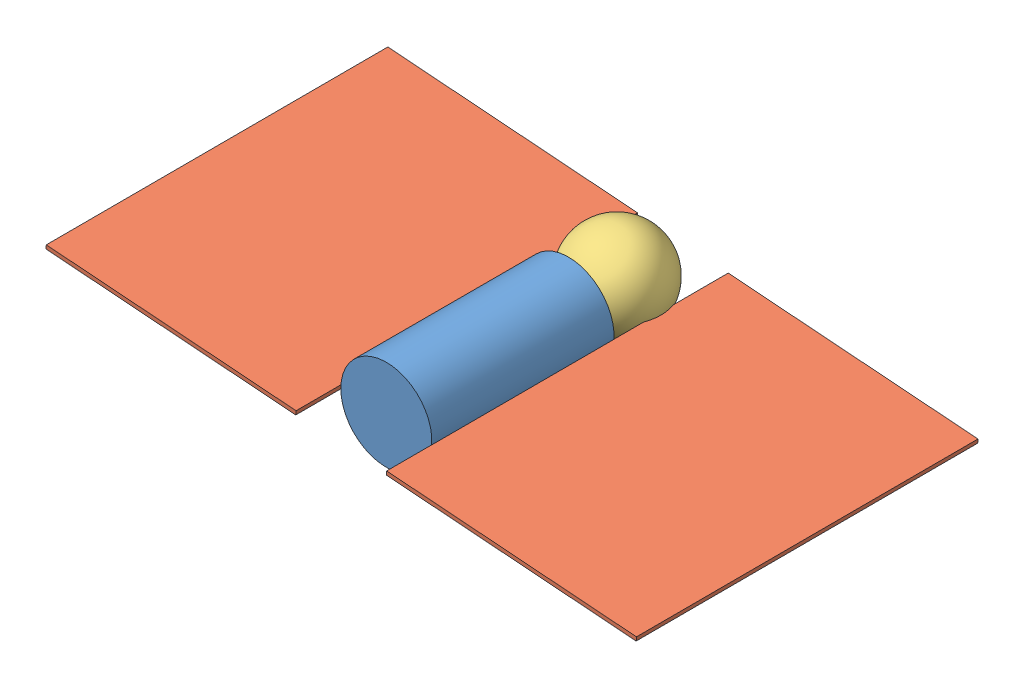
SolidWorks assembly Assem1, configuration Default. Lengths in mm.
Overall size (3951.55 667.68 2286.58).
4 component instances, 3 part files, 5 mates.
Components (placement in the parent):
- body_stand_in-1: body_stand_in [Default] at (260.872 470.1823 1151.1497) size (609.6 609.6 1219.2)
- wing_stand_in-1: wing_stand_in [Default] at (-1715.5894 597.5276 -779.4942) x (0.997171 -0.075171 -0.000136) z (0.000006 -0.001735 0.999998) size (1676.4 25.4 2286)
- wing_stand_in-2: wing_stand_in [Default] at (562.3795 425.8034 -779.8057) x (0.997171 -0.075171 -0.000136) z (0.000006 -0.001735 0.999998) size (1676.4 25.4 2286)
- head_stand_in-1: head_stand_in [Default] at (286.6823 528.2667 -7.4901) size (609.6 609.6 609.6)
Mates (geometry in assembly coordinates):
- Coincident1: coincident: line of body_stand_in-1 through (-43.928 470.1823 -14.191) axis (0.000006 -0.001735 0.999998); line of wing_stand_in-1 through (-43.9188 467.545 1506.2738) axis (-0.000006 0.001735 -0.999998)
- Parallel2: parallel: plane of wing_stand_in-1 through (-1713.68 622.8557 -779.4502) normal (-0.000006 0.001735 -0.999998); plane of wing_stand_in-2 through (564.2889 451.1315 -779.7618) normal (-0.000006 0.001735 -0.999998)
- Coincident3: coincident: plane of wing_stand_in-1 through (-1713.68 622.8557 -779.4502) normal (0.075172 0.997169 0.001729); plane of wing_stand_in-2 through (564.2889 451.1315 -779.7618) normal (0.075172 0.997169 0.001729)
- Coincident4: coincident: plane of wing_stand_in-1 through (-1713.68 622.8557 -779.4502) normal (-0.000006 0.001735 -0.999998); plane of wing_stand_in-2 through (564.2889 451.1315 -779.7618) normal (-0.000006 0.001735 -0.999998)
- Coincident5: coincident: point of body_stand_in-1; sphere of head_stand_in-1
